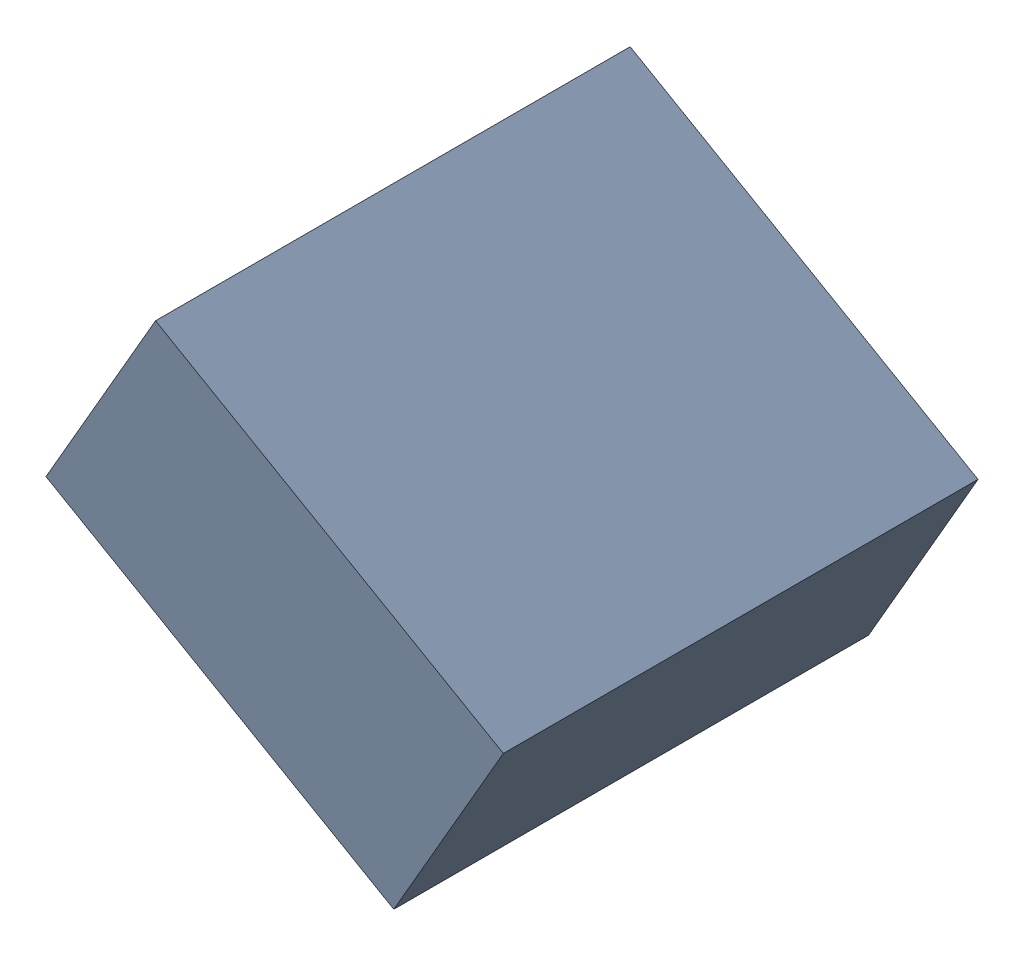
SolidWorks assembly C30_TDA6, configuration Standard. Lengths in mm.
Overall size (1.25 1.07 1.3).
2 component instances, 1 part files, 0 mates.
Components (placement in the parent):
- 885543056-1: 885543056 [Standard] at (-47.5295 35.0289 0) size (1.25 1.07 1.3)
  - Extruded_23-1: Extruded_23 [Standard] at origin size (1.25 1.07 1.3)
